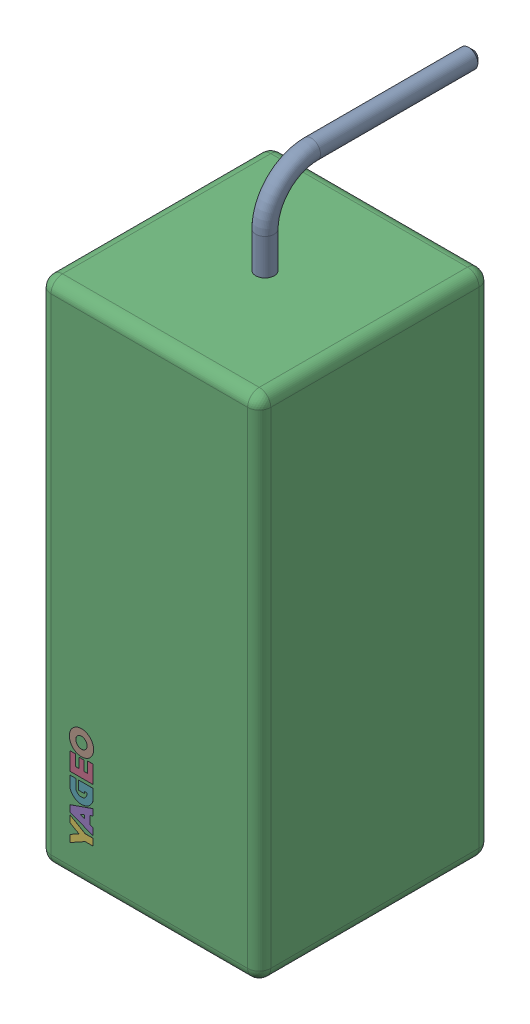
SolidWorks assembly R7.step, configuration Default. Lengths in mm.
Overall size (9.5 29.91 14).
4 component instances, 3 part files, 0 mates.
Components (placement in the parent):
- Res_Yageo_SQP500JB-1R2_eec.step-1: Res_Yageo_SQP500JB-1R2_eec.step [Default] at (85.725 21.209 0) x (0 1 0) z (0 0 1) size (29.91 9.5 14)
  - 1-6.step-1: 1-6.step [Default] at origin size (29.91 0.8 9.4)
  - 2-7.step-1: 2-7.step [Default] at origin size (22 9.5 10)
  - Yageo_Logo.step-1: Yageo_Logo.step [Default] at (-8.1443 3.6121 9.991) size (4.52 1.05 0.01)
